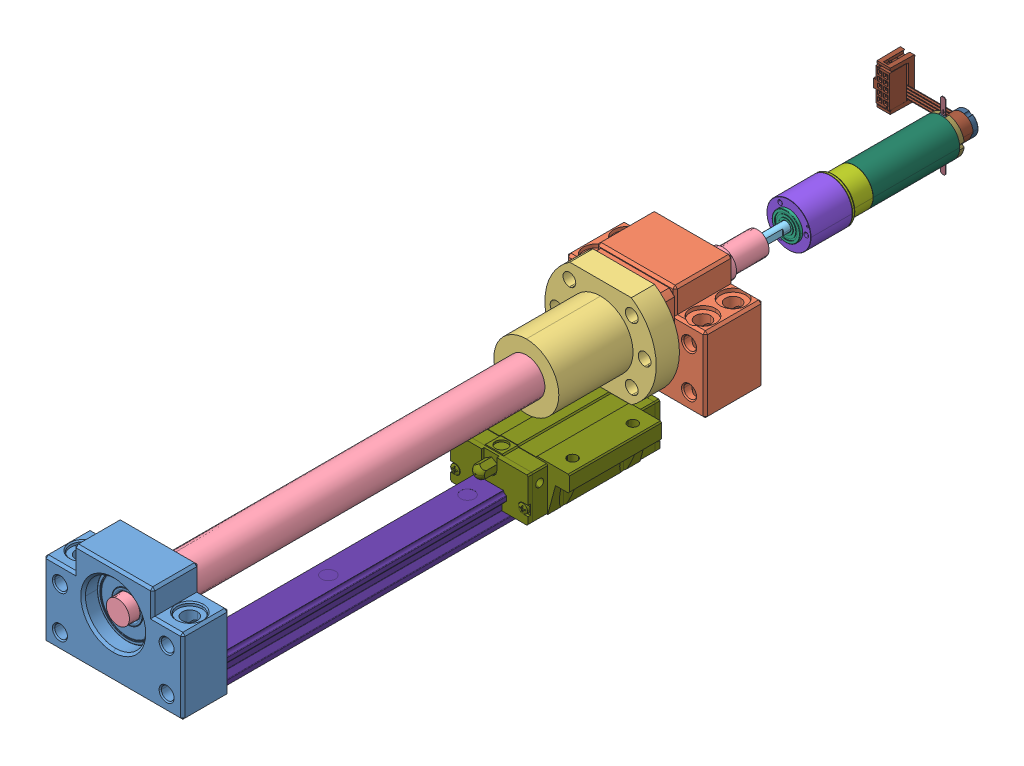
SolidWorks assembly ScrewAssembly_15cm, configuration Default. Lengths in mm.
Overall size (61 64 369.65).
18 component instances, 17 part files, 19 mates.
Components (placement in the parent):
- BF12.step-1: BF12.step [Default] at (-30 0 240.25) size (60 43 20)
- BK12.step-1: BK12.step [Default] at (-30 0 12.5) size (60 43 30.65)
- RM1605 Ball Nut STEP.step-1: RM1605 Ball Nut STEP.step [Default] at (-30 25 30.15) x (0 0 1) z (0 -1 0) size (42 48 40)
- RM1605-1: RM1605 [Default] at (-30 25 248.25) x (-0.470167 -0.882577 0) z (0 0 -1) size (16 16 275.75)
- gear metric configuration.stp-1: gear metric configuration.stp [Default] at (-30 25 -41) x (0 0 -1) z (1 0 0) size (91.9 29 40.5)
  - 0.stp-1: 0.stp [Default] at origin size (14.5 4 4)
  - 0-0.stp-1: 0-0.stp [Default] at origin size (4 12 12)
  - 0-1.stp-1: 0-1.stp [Default] at origin size (10.45 19 19)
  - 0-2.stp-1: 0-2.stp [Default] at origin size (17.97 19 19)
  - 0-3.stp-1: 0-3.stp [Default] at origin size (0.5 9.2 9.2)
  - 0-4.stp-1: 0-4.stp [Default] at origin size (2.88 10 10)
  - 0-5.stp-1: 0-5.stp [Default] at origin size (10.9 17.48 36)
  - 0-6.stp-1: 0-6.stp [Default] at origin size (2 15.64 15.71)
  - 0-7.stp-1: 0-7.stp [Default] at origin size (2.2 29 2.3)
  - 0-8.stp-1: 0-8.stp [Default] at origin size (2.1 15.8 15.45)
  - 0-9.stp-1: 0-9.stp [Default] at origin size (37.3 16 16)
- Carriage-1: Carriage [Default] at (-30 -19 130.632) x (1 0 0) z (0 1 0) size (52 63.99 19.5)
- Rail-1: Rail [Default] at (-30 -19 230) x (1 0 0) z (0 1 0) size (15 205 12.5)
Mates (geometry in assembly coordinates):
- Coincident5: coincident anti-aligned: plane of BK12.step-1 through (-60 0 25) normal (0 -1 0)
- Coincident6: coincident anti-aligned: plane of BF12.step-1 through (-60 0 250.25) normal (0 -1 0)
- Coincident7: coincident anti-aligned: plane of BK12.step-1 through (-60 0 0) normal (0 0 -1)
- Coincident8: coincident aligned: plane of BK12.step-1 through (0 0 25) normal (1 0 0)
- Concentric7: concentric aligned: cylinder of RM1605 Ball Nut STEP.step-1 through (-30 25 30.15) axis (0 0 1) radius 8; cylinder of RM1605-1 through (-30 25 248.25) axis (0 0 1) radius 8
- Coincident10: coincident anti-aligned: plane of BK12.step-1 through (-30 32.65 26.5) normal (0 0 1); plane of RM1605-1 through (-35.2955 27.821 26.5) normal (0 0 -1)
- Concentric8: concentric aligned: cylinder of BK12.step-1 through (-30 25 47.8429) axis (0 0 1) radius 6; cylinder of RM1605-1 through (-30 25 248.25) axis (0 0 1) radius 8
- Concentric9: concentric aligned: cylinder of BF12.step-1 through (-30 25 244.456) axis (0 0 1) radius 5; cylinder of RM1605-1 through (-30 25 248.25) axis (0 0 1) radius 5
- Coincident11: coincident anti-aligned: plane of BF12.step-1 through (-30 30 236.25) normal (0 0 -1); plane of RM1605-1 through (-37.0606 28.7613 236.25) normal (0 0 1)
- Concentric10: concentric aligned: cylinder of RM1605-1 through (-30 25 248.25) axis (0 0 1) radius 5; cylinder of gear metric configuration.stp-1/0.stp-1 through (-30 25 -34.75) axis (0 0 1) radius 2
- Parallel3: parallel aligned: plane of gear metric configuration.stp-1/0-5.stp-1 through (-57 37.475 -109.2) normal (0 1 0)
- Coincident20: coincident anti-aligned: plane of RM1605-1 through (-30 25 -27.5) normal (0 0 -1); plane of gear metric configuration.stp-1/0.stp-1 through (-30 25 -27.5) normal (0 0 1)
- Coincident21: coincident anti-aligned: plane of BK12.step-1 through (-60 0 25) normal (0 0 1); plane of Rail-1 through (-30 -12.8514 25) normal (0 0 -1)
- Width1: width anti-aligned: plane of Carriage-1 through (-22.5 -8.9 15.951) normal (-1 0 0); plane of Carriage-1 through (-37.5 -8.9 15.951) normal (1 0 0); plane of Rail-1 through (-22.5 -8.9 25) normal (1 0 0); plane of Rail-1 through (-37.5 -8.9 25) normal (-1 0 0)
- Coincident22: coincident anti-aligned: plane of Carriage-1 through (-30 -6.5 15.951) normal (0 -1 0); plane of Rail-1 through (-30 -6.5 25) normal (0 1 0)
- Coincident23: coincident: plane of RM1605 Ball Nut STEP.step-1 through (-30 25 30.15) normal (0 0 -1); point of Carriage-1
- Coincident24: coincident anti-aligned: plane of RM1605 Ball Nut STEP.step-1 through (-54.8624 5 30.15) normal (0 -1 0); plane of Carriage-1 through (-30 5 39.831) normal (0 1 0)
- Width2: width anti-aligned: plane of BK12.step-1 through (0 0 25) normal (1 0 0); plane of BK12.step-1 through (-60 32.5 25) normal (-1 0 0); plane of Carriage-1 through (-56 2 59.731) normal (-1 0 0); plane of Carriage-1 through (-4 1.5 39.831) normal (1 0 0)
- Coincident25: coincident anti-aligned: plane of BK12.step-1 through (-42 25 30.15) normal (0 0 1); plane of RM1605 Ball Nut STEP.step-1 through (-30 25 30.15) normal (0 0 -1)
